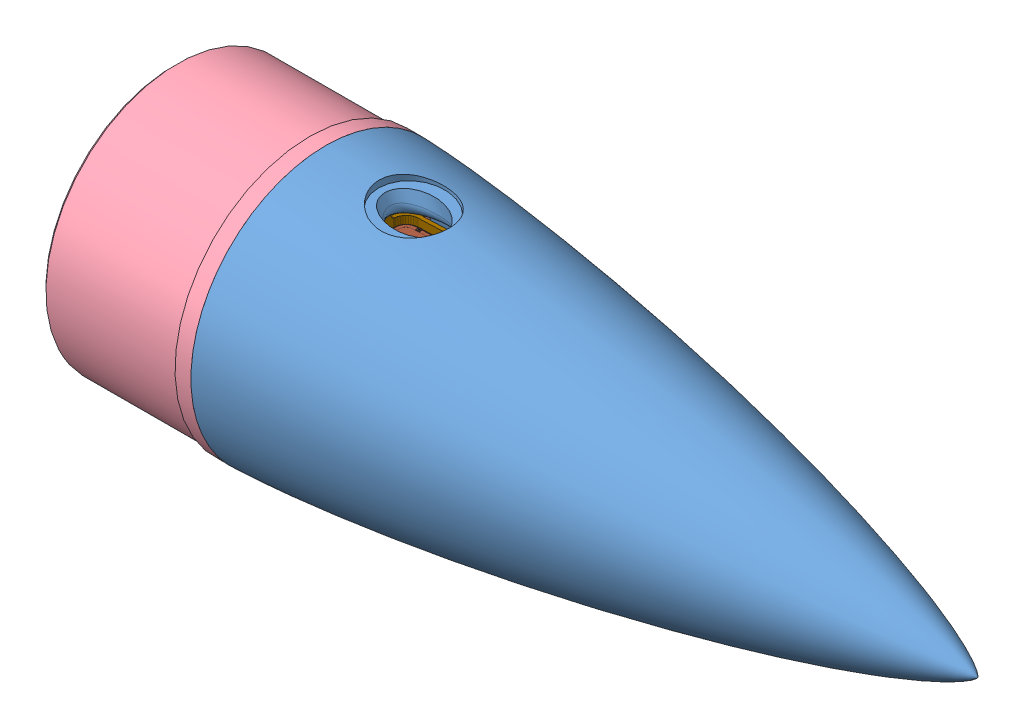
SolidWorks assembly Nosecone Assembly, configuration Default. Lengths in mm.
Overall size (504.08 230.99 230.99).
17 component instances, 11 part files, 24 mates.
Components (placement in the parent):
- Nosecone Prototype v5-1: Nosecone Prototype v5 [Default] at origin size (409.09 169.1 169.1)
- Nosecone Tap Insert-1: Nosecone Tap Insert [99362A500] at (10.691 34.775 60.2321) x (0 1 0) z (0 0 1) size (7.72 10.12 7.66)
- Nosecone Tap Insert-2: Nosecone Tap Insert [99362A500] at (10.691 -34.775 60.2321) x (0 0.5 0.866025) z (0 -0.866025 0.5) size (7.72 10.12 7.66)
- Nosecone Tap Insert-3: Nosecone Tap Insert [99362A500] at (10.691 -69.55 0) x (0 -0.5 0.866025) z (0 -0.866025 -0.5) size (7.72 10.12 7.66)
- Nosecone Tap Insert-4: Nosecone Tap Insert [99362A500] at (10.691 -34.775 -60.2321) x (0 -1 0) z (0 0 -1) size (7.72 10.12 7.66)
- Nosecone Tap Insert-5: Nosecone Tap Insert [99362A500] at (10.691 34.775 -60.2321) x (0 -0.5 -0.866025) z (0 0.866025 -0.5) size (7.72 10.12 7.66)
- Nosecone Tap Insert-6: Nosecone Tap Insert [99362A500] at (10.691 69.55 0) x (0 0.5 -0.866025) z (0 0.866025 0.5) size (7.72 10.12 7.66)
- Nosecone Plate Screw-1: Nosecone Plate Screw [92949A245] at (-12.1691 34.775 60.2321) x (0 0 1) z (-1 0 0) size (9.17 9.17 22.21)
- NoseBottom-1: NoseBottom [Default] at (0.3963 0 0) x (0 0.5 -0.866025) z (1 0 0) size (169.1 169.1 95)
- Eggfinder tx-1: Eggfinder tx [Default] at (3.3963 -0.9296 59.9106) x (0 -0.731337 -0.682017) z (0 -0.682017 0.731337) size (79.57 81.62 22.8)
- gps mount-1: gps mount [Default] at (0.3963 -43.4582 -11.0624) x (0 0.731337 0.682017) z (0 0.682017 -0.731337) size (82 4 25)
- battery-1: battery [Default] at (10.3963 3.0034 -61.7237) x (0 -0.794877 0.606771) z (0 -0.606771 -0.794877) size (55.7 10 30.6)
- battery holders-1: battery holders [Default] at (0.3963 -44.0745 -28.3028) x (0 0.794877 -0.606771) z (0 -0.606771 -0.794877) size (21 14 21)
- battery holders-2: battery holders [Default] at (0.3963 24.3739 -37.0243) x (0 -0.794877 0.606771) z (0 0.606771 0.794877) size (21 14 21)
- mountgopro-1: mountgopro [Default] at (30.3312 16.2364 -21.4743) x (0 0.006286 0.99998) z (-0.037908 0.999262 -0.006282) size (46.89 61.42 48.15)
- Nosecone GoPro Mount-1: Nosecone GoPro Mount [Default] at (23.3963 25.9103 9.8334) x (0 0.99998 -0.006286) z (0 -0.006286 -0.99998) size (45 30.24 45)
- GoPro Session-1: GoPro Session [Default] at (53.2294 36.3894 2.0188) x (0 0.006286 0.99998) z (-0.037908 0.999262 -0.006282) size (38 38 36.25)
Mates (geometry in assembly coordinates):
- Concentric13: concentric anti-aligned: cylinder of Nosecone Prototype v5-1 through (0.3953 34.775 60.2321) axis (-1 0 0) radius 3.3782; circle of Nosecone Tap Insert-1
- Lock1: lock: unknown of Nosecone Prototype v5-1; unknown of Nosecone Tap Insert-1
- Coincident11: coincident anti-aligned: plane of Nosecone Prototype v5-1 through (0.3953 69.55 0) normal (-1 0 0); plane of NoseBottom-1 through (0.3953 -42.275 73.2224) normal (1 0 0)
- Concentric15: concentric anti-aligned: cylinder of Nosecone Prototype v5-1 through (444.767 0 0) axis (1 0 0) radius 64.55; cylinder of NoseBottom-1 through (-99.3537 0 0) axis (-1 0 0) radius 82.55
- Concentric16: concentric aligned: circle of Nosecone Tap Insert-2; cylinder of NoseBottom-1 through (0.3963 -34.775 60.2321) axis (-1 0 0) radius 2.41
- Coincident12: coincident anti-aligned: plane of Nosecone Plate Screw-1 through (-9.6037 30.1903 60.2321) normal (1 0 0); plane of NoseBottom-1 through (-9.6037 8.0983 33.8189) normal (-1 0 0)
- Concentric17: concentric aligned: circle of Nosecone Plate Screw-1; cylinder of NoseBottom-1 through (0.3963 34.775 60.2321) axis (-1 0 0) radius 2.41
- Coincident13: coincident anti-aligned: plane of NoseBottom-1 through (0.3963 -34.775 60.2321) normal (1 0 0); plane of gps mount-1 through (0.3963 -43.4582 -11.0624) normal (-1 0 0)
- Concentric18: concentric aligned: cylinder of Eggfinder tx-1 through (5.0163 -49.409 -0.8873) axis (-1 0 0) radius 1.65; cylinder of gps mount-1 through (3.3963 -49.409 -0.8873) axis (-1 0 0) radius 1.5875
- Coincident17: coincident anti-aligned: plane of NoseBottom-1 through (0.3963 -34.775 60.2321) normal (1 0 0); plane of battery-1 through (0.3963 3.0034 -61.7237) normal (-1 0 0)
- Coincident19: coincident anti-aligned: plane of NoseBottom-1 through (0.3963 -34.775 60.2321) normal (1 0 0); plane of battery holders-1 through (0.3963 -44.0745 -28.3028) normal (-1 0 0)
- Coincident21: coincident anti-aligned: plane of battery-1 through (0.3963 3.0034 -61.7237) normal (0 -0.606771 -0.794877); plane of battery holders-1 through (12.3963 -42.861 -26.713) normal (0 0.606771 0.794877)
- Coincident22: coincident anti-aligned: plane of battery-1 through (0.3963 -41.2712 -27.9266) normal (0 -0.794877 0.606771); plane of battery holders-1 through (12.3963 -42.4848 -29.5163) normal (0 0.794877 -0.606771)
- Coincident24: coincident anti-aligned: plane of NoseBottom-1 through (0.3963 -34.775 60.2321) normal (1 0 0); plane of battery holders-2 through (0.3963 24.3739 -37.0243) normal (-1 0 0)
- Coincident25: coincident anti-aligned: plane of battery-1 through (0.3963 3.0034 -61.7237) normal (0 0.794877 -0.606771); plane of battery holders-2 through (12.3963 22.7841 -35.8107) normal (0 -0.794877 0.606771)
- Coincident26: coincident anti-aligned: plane of battery-1 through (0.3963 21.5706 -37.4005) normal (0 0.606771 0.794877); plane of battery holders-2 through (12.3963 23.1604 -38.614) normal (0 -0.606771 -0.794877)
- Coincident27: coincident anti-aligned: plane of NoseBottom-1 through (0.3963 -34.775 60.2321) normal (1 0 0); plane of Nosecone GoPro Mount-1 through (0.3963 52.5009 24.1665) normal (-1 0 0)
- Coincident30: coincident anti-aligned: plane of NoseBottom-1 through (0.3963 -34.775 60.2321) normal (1 0 0); plane of Nosecone GoPro Mount-1 through (0.3963 52.5009 24.1665) normal (-1 0 0)
- Coincident31: coincident anti-aligned: plane of mountgopro-1 through (71.68 51.2971 11.9253) normal (-0.999281 -0.037907 0.000238); plane of GoPro Session-1 through (71.5287 55.3407 20.9001) normal (0.999281 0.037907 -0.000238)
- Coincident32: coincident anti-aligned: plane of mountgopro-1 through (42.2012 50.2354 20.9322) normal (0 -0.006286 -0.99998); plane of GoPro Session-1 through (33.556 53.9002 20.9091) normal (0 0.006286 0.99998)
- Coincident33: coincident: plane of mountgopro-1 through (72.694 24.449 -6.6563) normal (-0.037908 0.999262 -0.006282); line of GoPro Session-1 through (72.694 24.5636 11.5834) axis (0 -0.006286 -0.99998)
- Coincident34: coincident anti-aligned: plane of mountgopro-1 through (30.8997 64.4359 -0.009) normal (0 0.006286 0.99998); plane of Nosecone GoPro Mount-1 through (23.3963 25.8499 0.2336) normal (0 -0.006286 -0.99998)
- Coincident38: coincident anti-aligned: plane of Eggfinder tx-1 through (3.3963 -0.9296 59.9106) normal (-1 0 0); plane of gps mount-1 through (3.3963 -43.4582 -11.0624) normal (1 0 0)
- Parallel5: parallel anti-aligned: plane of Eggfinder tx-1 through (5.0163 -0.9296 59.9106) normal (0 -0.682017 0.731337); plane of gps mount-1 through (4.3963 -59.1446 5.7583) normal (0 0.682017 -0.731337)
